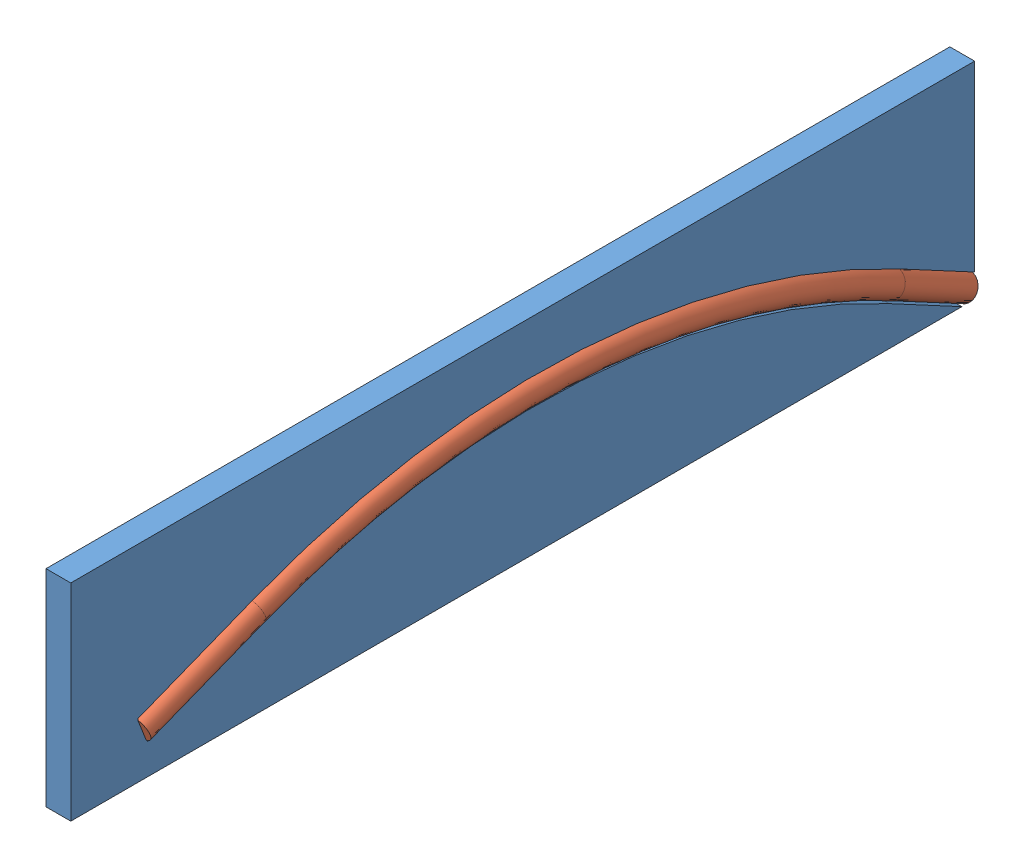
SolidWorks assembly Montagem2, configuration Valor predeterminado. Lengths in mm.
Overall size (8 176.59 220.53).
2 component instances, 2 part files, 3 mates.
Components (placement in the parent):
- Gabarito Eixo Curvo-1: Gabarito Eixo Curvo [Valor predeterminado] at origin size (6 50 219.03)
- BDT_G_F_05_v01-1: BDT_G_F_05_v01 [Valor predeterminado] at (6.9652 76.6138 133.3169) x (0 0.880872 0.473354) z (-1 0 0) size (106.05 175.71 6)
Mates (geometry in assembly coordinates):
- Tangente2: tangent: plane of Gabarito Eixo Curvo-1 through (3.9652 0 0) normal (1 0 0); cylinder of BDT_G_F_05_v01-1 through (6.9652 160.3157 95.6592) axis (0 0.366482 -0.930425) radius 3
- Coincidente3: coincident: plane of Gabarito Eixo Curvo-1 through (1.9652 -9.45 -17.6266) normal (0 -0.472501 -0.88133); plane of BDT_G_F_05_v01-1 through (6.9652 152.8054 -104.6154) normal (0 -0.472501 -0.88133)
- Distância1: distance = 0.3 mm: cylinder of BDT_G_F_05_v01-1 through (6.9652 162.4161 -87.0749) axis (0 -0.472501 -0.88133) radius 3; line of Gabarito Eixo Curvo-1 through (7.9652 165.1877 -88.5609) axis (0 -0.472501 -0.88133)
